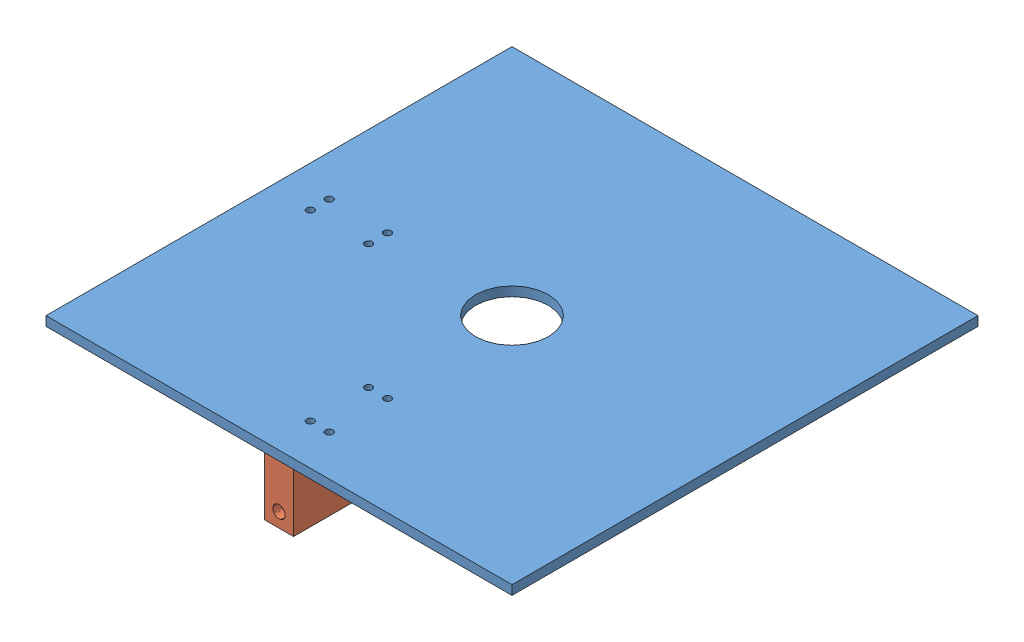
SolidWorks assembly Top Plate Assembly, configuration Default. Lengths in mm.
Overall size (203.2 29.46 203.2).
3 component instances, 2 part files, 9 mates.
Components (placement in the parent):
- Top Plate-1: Top Plate [Default] at origin size (203.2 4.06 203.2)
- top plate connection-1: top plate connection [Default] at (0 -25.4 76.2) x (0 0 1) z (-1 0 0) size (50.8 25.4 12.7)
- top plate connection-2: top plate connection [Default] at (-76.2 -25.4 0) x (-1 0 0) z (0 0 -1) size (50.8 25.4 12.7)
Mates (geometry in assembly coordinates):
- Coincident1: coincident aligned: plane of Top Plate-1 through (-143.6493 4.064 -3.1622) normal (-0.722498 0 0.691373); plane of top plate connection-1 through (-4.3902 0 142.366) normal (-0.722498 0 0.691373)
- Coincident2: coincident anti-aligned: plane of Top Plate-1 through (0 0 0) normal (0 -1 0); plane of top plate connection-1 through (18.3514 0 129.393) normal (0 1 0)
- Concentric1: concentric anti-aligned: cylinder of ? through (0 4.064 0) axis (0 1 0) radius 15.875
- Coincident4: coincident anti-aligned: plane of Top Plate-1 through (0 0 0) normal (0 -1 0); plane of assembly through (0 0 0) normal (0 1 0)
- Coincident5: coincident: moEndPointRef_w of ?
- Coincident6: coincident anti-aligned: plane of Top Plate-1 through (0 0 0) normal (0 -1 0); plane of top plate connection-2 through (-52.6827 0 -55.0543) normal (0 1 0)
- Concentric2: concentric aligned: cylinder of Top Plate-1 through (-60.933 4.064 -57.7061) axis (0 1 0) radius 1.5875; cylinder of top plate connection-2 through (-60.933 0 -57.7061) axis (0 1 0) radius 1.3208
- Concentric3: concentric aligned: cylinder of Top Plate-1 through (-37.4079 4.064 -45.062) axis (0 1 0) radius 1.5875; cylinder of top plate connection-2 through (-37.4079 0 -45.062) axis (0 1 0) radius 1.3208
- Concentric4: concentric aligned: cylinder of Top Plate-1 through (4.1275 4.064 58.42) axis (0 1 0) radius 1.5875; cylinder of top plate connection-1 through (4.1275 0 58.42) axis (0 1 0) radius 1.3208
